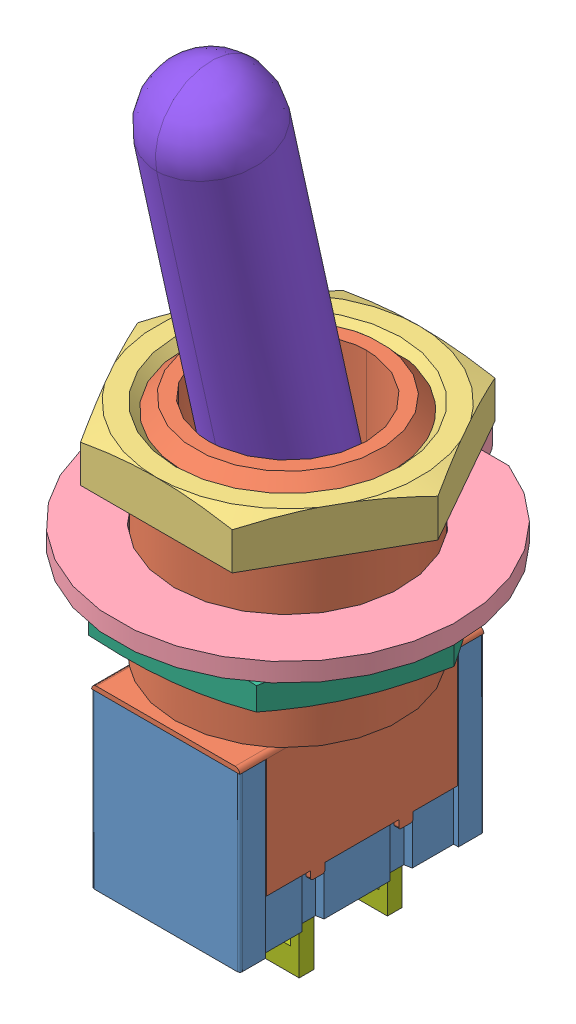
SolidWorks assembly M2011B2B1W01, configuration Default. Lengths in mm.
Overall size (18.21 44.24 19.49).
8 component instances, 8 part files, 7 mates.
Components (placement in the parent):
- _M20112B2B1W01_switch_2-1: _M20112B2B1W01_switch_2 [Default] at origin size (7.9 9.17 13)
- _M201B1M201_bushing_4-1: _M201B1M201_bushing_4 [Default] at (0 -0.254 0) size (12 19.04 13)
- _AT503M_6-1: _AT503M_6 [Default] at (0 10.5308 0) x (1 0 0) z (0 1 0) size (16.01 15.91 2.39)
- _AT506M_8-1: _AT506M_8 [Default] at (0 5.1714 0) x (0 0 1) z (0 1 0) size (18.62 18.21 2.79)
- _AT508_10-1: _AT508_10 [Default] at (0 4.9174 0) x (1 0 0) z (0 -1 0) size (15.8 15.8 0.51)
- _AT527M_12-1: _AT527M_12 [Default] at (0 3.6601 0) x (0.993403 0 -0.114675) z (0 -1 0) size (16.01 17.77 2.01)
- _M201101_terminals_14-1: _M201101_terminals_14 [Default] at (0 -9.4234 0) size (6.38 5 12.5)
- _M20B2_toggles_16-1: _M20B2_toggles_16 [Default] at (0 11.9888 0) x (0 0 -1) z (1 0 0) size (11.39 26.26 5.99)
Mates (geometry in assembly coordinates):
- Concentric1: concentric aligned: cylinder of _M201B1M201_bushing_4-1 through (0 -0.127 0) axis (0 1 0) radius 6; cylinder of _AT506M_8-1 through (0 6.162 0) axis (0 1 0) radius 9.1059
- Coincident1: coincident anti-aligned: plane of _AT506M_8-1 through (0 5.1714 0) normal (0 -1 0); plane of _AT508_10-1 through (0 5.1714 0) normal (0 1 0)
- Parallel1: parallel aligned: plane of _M20112B2B1W01_switch_2-1 through (3.8197 -9.4234 -6.5024) normal (0 0 -1); plane of _AT506M_8-1 through (1.397 5.6667 -9.5123) normal (0 0 -1)
- Concentric2: concentric anti-aligned: cylinder of _M201B1M201_bushing_4-1 through (0 -0.127 0) axis (0 1 0) radius 6; cylinder of _AT508_10-1 through (0 4.6634 0) axis (0 -1 0) radius 7.8994
- Concentric3: concentric aligned: cylinder of _AT508_10-1 through (0 4.6634 0) axis (0 -1 0) radius 7.8994; cylinder of _AT527M_12-1 through (0 4.6634 0) axis (0 -1 0) radius 5.053
- Coincident2: coincident anti-aligned: plane of _AT508_10-1 through (0 4.6634 0) normal (0 -1 0); plane of _AT527M_12-1 through (0.8025 4.6634 6.9515) normal (0 1 0)
- Distance1: distance = 3.175 mm anti-aligned: plane of _AT506M_8-1 through (0 6.162 0) normal (0 1 0); plane of _AT503M_6-1 through (0 9.337 -8.3972) normal (0 -1 0)
